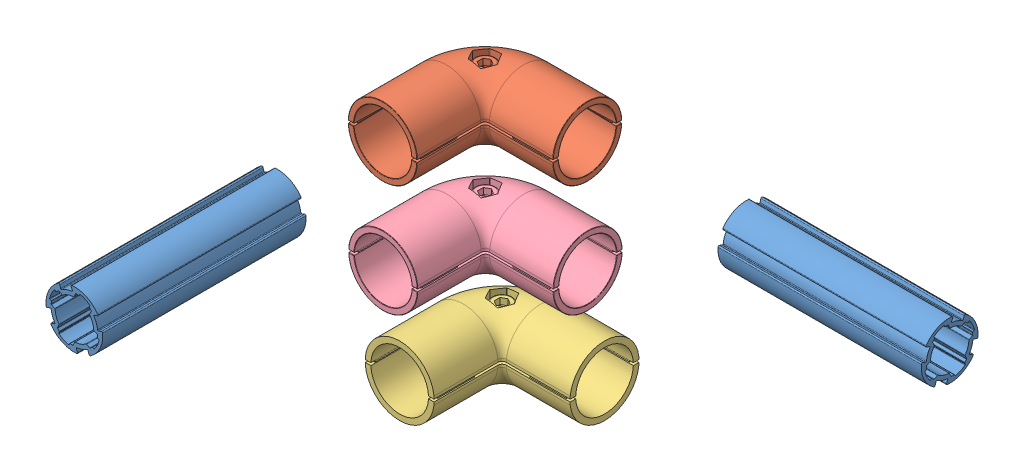
SolidWorks assembly TFS.D28.2.01.01, configuration По умолчанию. Lengths in mm.
Overall size (254.03 79.62 225.96).
5 component instances, 4 part files, 5 mates.
Components (placement in the parent):
- TFS.D28.1 копия-1: TFS.D28.1 копия [默认] at (157.4097 1508.9757 224.7633) x (0 -0.901758 -0.432241) z (-1 0 0) size (28 28 100)
- TFS.D28.2.01.01 копия 2-1: TFS.D28.2.01.01 копия 2 [По умолчанию] at (-52.0279 3.0034 93.799) size (81.71 34.11 80.16)
- TFS.D28.1 копия-2: TFS.D28.1 копия [默认] at (70.4338 1509.5654 179.1253) x (-0.428561 -0.903513 0) z (0 0 1) size (28 28 100)
- TFS.D28.2.01.01-1: TFS.D28.2.01.01 [默认] at (11.2509 -39.8868 148.6798) size (67.29 36.1 67.29)
- TFS.D28.2.01.01 копия-1: TFS.D28.2.01.01 копия [默认] at (-5.6954 -5.8543 139.9351) size (67.29 36.1 67.29)
Mates (geometry in assembly coordinates):
- Параллельность1: parallel: plane of TFS.D28.2.01.01 копия 2-1 through (14.7766 16.4087 -20.5563) normal (0 1 0); plane of assembly through (0 0 0) normal (0 1 0)
- Параллельность2: parallel: plane of TFS.D28.2.01.01 копия 2-1 through (-52.2029 -1.0428 93.9331) normal (0 0 1); plane of assembly through (0 0 0) normal (0 0 1)
- Параллельность3: parallel: plane of TFS.D28.2.01.01 копия 2-1 through (-20.8029 17.0087 77.0437) normal (1 0 0); plane of assembly through (0 0 0) normal (1 0 0)
- Концентричный1: concentric: cylinder of TFS.D28.1 копия-1 through (57.4097 17.0087 77.0437) axis (1 0 0) radius 14; cylinder of TFS.D28.2.01.01 копия 2-1 through (-41.8029 17.0087 77.0437) axis (1 0 0) radius 14.2
- Концентричный2: concentric: cylinder of TFS.D28.2.01.01 копия 2-1 through (-71.2029 17.0087 106.4437) axis (0 0 1) radius 14.2; cylinder of TFS.D28.1 копия-2 through (-71.2029 17.0087 279.1253) axis (0 0 -1) radius 14
